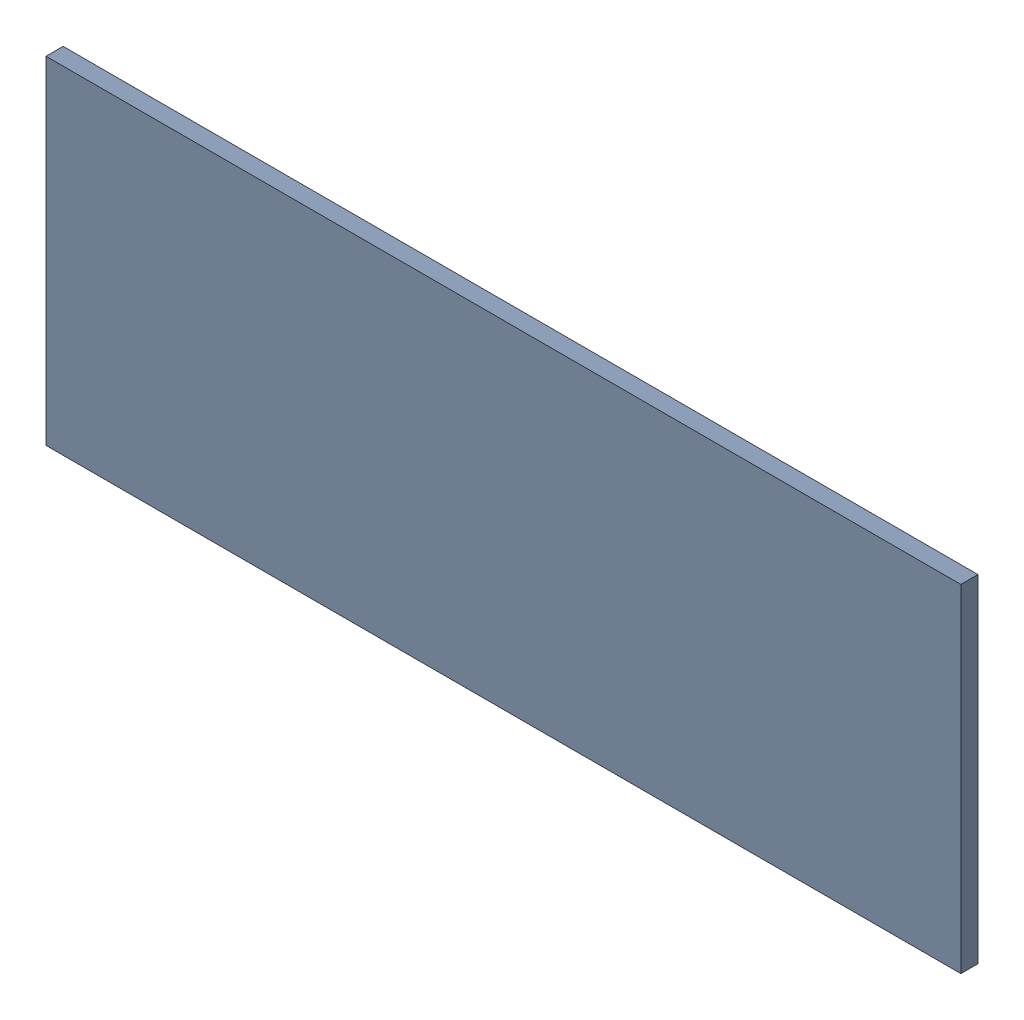
SolidWorks assembly Pad RAK4600-31(29.2mm,23.75mm) on Top Layer, configuration Predeterminado. Lengths in mm.
Overall size (1.9 0.7 0.04).
2 component instances, 1 part files, 0 mates.
Components (placement in the parent):
- Pad RAK4600-31(29.2mm,23.75mm) on Top Layer-1-1: Pad RAK4600-31(29.2mm,23.75mm) on Top Layer-1 [Predeterminado] at (-68.317 -44.187 -0.0457) size (1.9 0.7 0.04)
  - Pad RAK4600-31(29.2mm,23.75mm) on Top Layer-Part-1-1: Pad RAK4600-31(29.2mm,23.75mm) on Top Layer-Part-1 [Predeterminado] at origin size (1.9 0.7 0.04)
